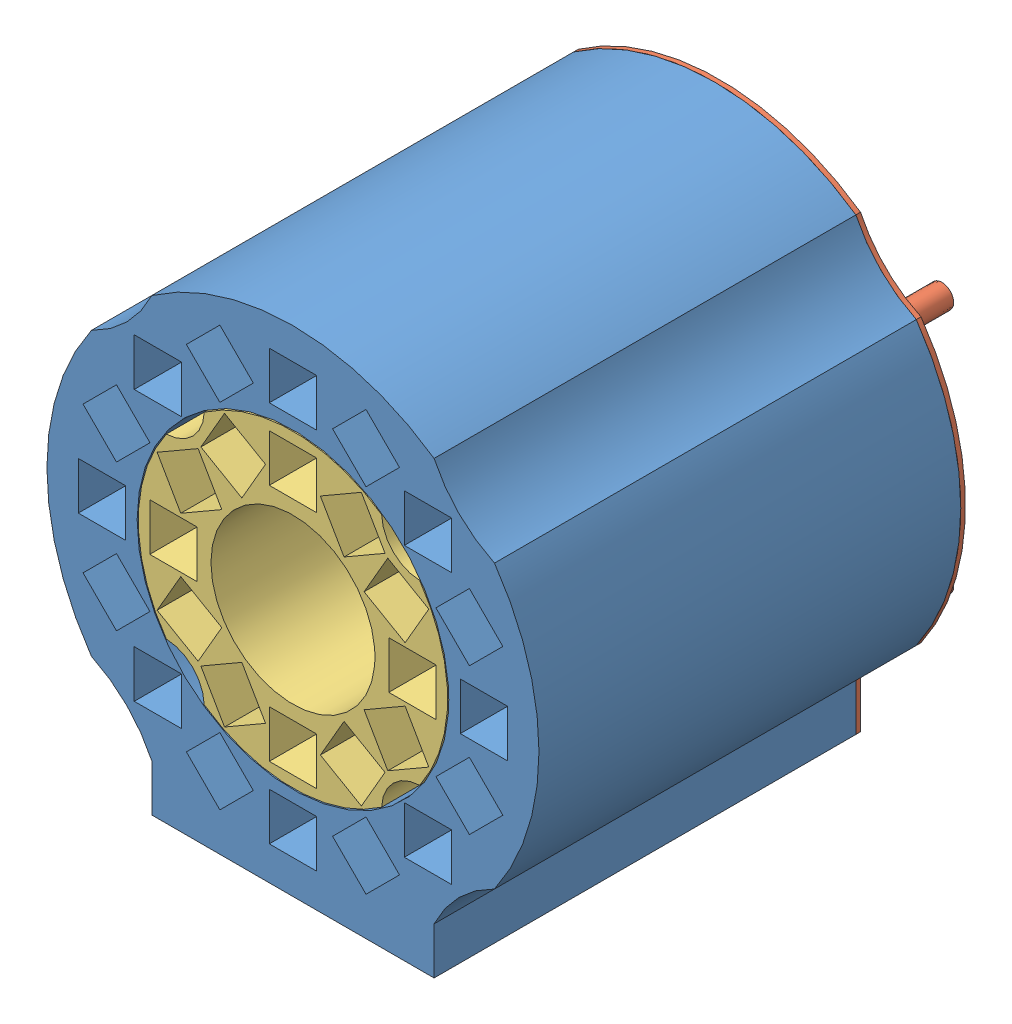
SolidWorks assembly full, configuration Default. Lengths in mm.
Overall size (105 105.51 101).
6 component instances, 4 part files, 2 mates.
Components (placement in the parent):
- outside_ring-1: outside_ring [Default] at (126.3147 119.1007 -8.3978) size (105 105.51 101)
  - outside_ring-1: outside_ring [Default] at (11.7274 48.3118 100.1613) size (105 105.51 90)
  - outside_ring_cap-1: outside_ring_cap [Default] at (11.7274 48.3118 99.1613) size (105 105.51 11)
- inside_ring-1: inside_ring [Default] at (122.3776 115.4552 16.6097) size (66 66 101)
  - inside_ring-1: inside_ring [Default] at (15.6645 51.9573 75.1538) size (66 66 90)
  - inside_ring_cap-1: inside_ring_cap [Default] at (15.6645 51.9573 64.1538) size (66 66 11)
Mates (geometry in assembly coordinates):
- Concentric1: concentric: circle of outside_ring-1/outside_ring-1; circle of inside_ring-1/inside_ring-1
- Coincident1: coincident: plane of outside_ring-1/outside_ring-1 through (138.0421 167.4125 181.7635) normal (0 0 1); plane of inside_ring-1/inside_ring-1 through (138.0421 167.4125 181.7635) normal (0 0 1)
